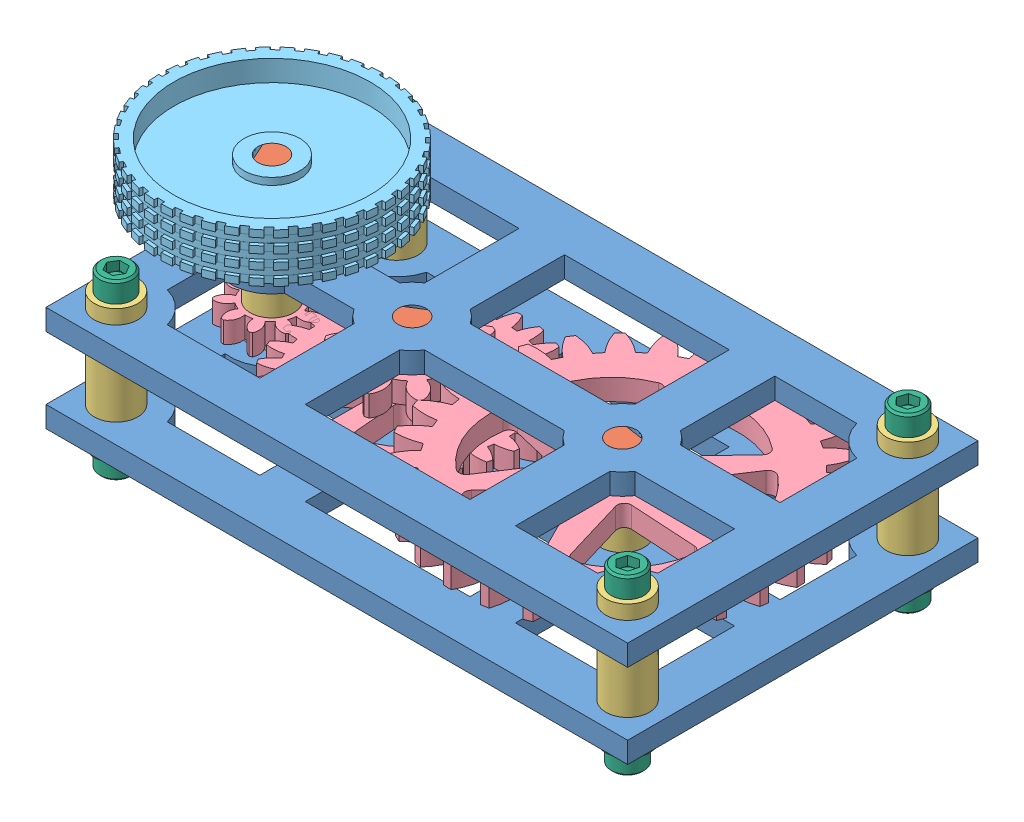
SolidWorks assembly gearbox, configuration Default. Lengths in mm.
Overall size (99.85 37 54.33).
40 component instances, 6 part files, 46 mates.
Components (placement in the parent):
- plate-1: plate [Default] at (38.6183 41.2448 69.3002) size (83 3 50)
- subassem1-1: subassem1 [Default] at (-22.9278 69.7398 72.0487) x (0.409476 0 0.912321) z (0.912321 0 -0.409476) size (12 25 11.53)
  - axel-1: axel [25 tall] at (8.6695 3.495 26.0282) size (4 25 3.5)
  - spacer-1: spacer [1 mm tall] at (8.6695 24.495 26.0282) x (0.916375 0 -0.400322) z (0.400322 0 0.916375) size (6.2 1 6.2)
  - spacer-2: spacer [5mm tall] at (8.6695 16.495 26.0282) x (-0.921754 0 0.387775) z (-0.387775 0 -0.921754) size (6.2 5 6.2)
  - root_gear-1: root_gear [10T 1.0Mod] at (8.6695 21.495 26.0282) size (12 3 11.53)
- subassem2-1: subassem2 [Default] at (24.0007 53.9541 53.6802) x (-0.845445 0 0.534063) z (0.534063 0 0.845445) size (32 15 31.89)
  - root_gear-3: root_gear [30T 1.0Mod] at (8.0314 5.7093 13.4022) size (32 3 31.89)
  - root_gear-4: root_gear [10T 1.5Mod] at (8.0314 1.7093 13.4022) size (18 3 17.3)
  - axel-1: axel [15 tall] at (8.0314 -2.2907 13.4022) size (4 15 3.5)
  - spacer-1: spacer [1 mm tall] at (8.0314 0.7093 13.4022) x (-0.679343 0 -0.733821) z (0.733821 0 -0.679343) size (6.2 1 6.2)
  - spacer-2: spacer [1 mm tall] at (8.0314 4.7093 13.4022) x (0.793961 0 -0.607968) z (0.607968 0 0.793961) size (6.2 1 6.2)
  - spacer-3: spacer [1 mm tall] at (8.0314 8.7093 13.4022) x (0.998465 0 -0.055384) z (0.055384 0 0.998465) size (6.2 1 6.2)
- subassem3-1: subassem3 [Default] at (45.6057 27.3395 43.9522) x (0.989309 0 0.145833) z (-0.145833 0 0.989309) size (48 25 47.84)
  - axel-1: axel [25 tall] at (12.3654 3.9053 23.7992) size (4 25 3.5)
  - root_gear-1: root_gear [30T 1.5Mod] at (12.3654 21.9053 23.7992) size (48 3 47.84)
  - spacer-1: spacer [1 mm tall] at (12.3654 24.9053 23.7992) x (0.97373 0 -0.227706) z (0.227706 0 0.97373) size (6.2 1 6.2)
  - spacer-2: spacer [5mm tall] at (12.3654 16.9053 23.7992) size (6.2 5 6.2)
- knob-1: knob [Default] at (4.3683 61.2448 69.3002) x (0 1 0) z (0.692524 0 0.721395) size (7 31.99 31.98)
- plate-2: plate [Default] at (38.6183 53.2448 69.3002) size (83 3 50)
- spacer-1: spacer [2.85 mm ID] at (2.1183 44.2448 89.3002) x (0.5813 0 0.813689) z (-0.813689 0 0.5813) size (6.2 9 6.2)
- spacer-2: spacer [2.85 mm ID] at (75.1183 44.2448 49.3002) x (0.5813 0 0.813689) z (-0.813689 0 0.5813) size (6.2 9 6.2)
- spacer-3: spacer [2.85 mm ID] at (2.1183 44.2448 49.3002) x (0.408871 0 0.912592) z (-0.912592 0 0.408871) size (6.2 9 6.2)
- spacer-4: spacer [2.85 mm ID] at (75.1183 44.2448 89.3002) x (0.525156 0 0.851006) z (-0.851006 0 0.525156) size (6.2 9 6.2)
- spacer-5: spacer [smaller 2.85 mm ID] at (2.1183 56.2448 89.3002) x (0.059353 0 0.998237) z (-0.998237 0 0.059353) size (6.2 2.02 6.2)
- spacer-6: spacer [smaller 2.85 mm ID] at (2.1183 56.2448 49.3002) x (-0.028098 0 0.999605) z (-0.999605 0 -0.028098) size (6.2 2.02 6.2)
- spacer-7: spacer [smaller 2.85 mm ID] at (75.1183 39.2198 49.3002) x (0.564051 0 0.82574) z (-0.82574 0 0.564051) size (6.2 2.02 6.2)
- spacer-8: spacer [smaller 2.85 mm ID] at (75.1183 41.2448 89.3002) x (-0.292272 0 0.956335) z (0.956335 0 0.292272) size (6.2 2.02 6.2)
- spacer-9: spacer [smaller 2.85 mm ID] at (2.1183 41.2448 89.3002) x (-0.425806 0 0.904815) z (0.904815 0 0.425806) size (6.2 2.02 6.2)
- spacer-10: spacer [smaller 2.85 mm ID] at (2.1183 41.2448 49.3002) x (-0.591521 0 0.806289) z (0.806289 0 0.591521) size (6.2 2.02 6.2)
- spacer-11: spacer [smaller 2.85 mm ID] at (75.1183 56.2448 89.3002) x (-0.618307 0 0.785937) z (-0.785937 0 -0.618307) size (6.2 2.02 6.2)
- spacer-12: spacer [smaller 2.85 mm ID] at (75.1183 56.2448 49.3002) x (0.472536 0 0.881311) z (-0.881311 0 0.472536) size (6.2 2.02 6.2)
- socket head cap screw_ai-1: socket head cap screw_ai [HX-SHCS 0.112-40x0.375x0.375-N] at (75.1183 36.375 89.3002) x (0 1 0) z (-0.37265 0 0.927972) size (12.37 4.65 4.65)
- socket head cap screw_ai-2: socket head cap screw_ai [HX-SHCS 0.112-40x0.375x0.375-N] at (75.1183 61.1146 89.3002) x (0 -1 0) z (0.2511 0 0.967961) size (12.37 4.65 4.65)
- socket head cap screw_ai-3: socket head cap screw_ai [HX-SHCS 0.112-40x0.375x0.375-N] at (2.1183 36.375 89.3002) x (0 1 0) z (-0.769807 0 -0.638277) size (12.37 4.65 4.65)
- socket head cap screw_ai-4: socket head cap screw_ai [HX-SHCS 0.112-40x0.375x0.375-N] at (2.1183 61.1146 49.3002) x (0 -1 0) z (0.951892 0 -0.306432) size (12.37 4.65 4.65)
- socket head cap screw_ai-5: socket head cap screw_ai [HX-SHCS 0.112-40x0.375x0.375-N] at (75.1183 61.1146 49.3002) x (0 -1 0) z (0.214562 0 0.97671) size (12.37 4.65 4.65)
- socket head cap screw_ai-6: socket head cap screw_ai [HX-SHCS 0.112-40x0.375x0.375-N] at (75.1183 36.375 49.3002) x (0 1 0) z (0.568945 0 -0.822375) size (12.37 4.65 4.65)
- socket head cap screw_ai-7: socket head cap screw_ai [HX-SHCS 0.112-40x0.375x0.375-N] at (2.1183 36.375 49.3002) x (0 1 0) z (-0.639188 0 0.769051) size (12.37 4.65 4.65)
- socket head cap screw_ai-8: socket head cap screw_ai [HX-SHCS 0.112-40x0.375x0.375-N] at (2.1183 61.1146 89.3002) x (0 -1 0) z (0.869562 0 -0.493824) size (12.37 4.65 4.65)
Mates (geometry in assembly coordinates):
- Coincident2: coincident: plane of plate-1 through (38.6183 44.2448 69.3002) normal (0 1 0); plane of subassem2-1/spacer-3 through (24.3683 44.2448 69.3002) normal (0 -1 0)
- Concentric2: concentric: cylinder of plate-1 through (24.3683 44.2448 69.3002) axis (0 -1 0) radius 2; cylinder of subassem2-1/axel-1 through (24.3683 41.2448 69.3002) axis (0 1 0) radius 2
- Concentric3: concentric: cylinder of plate-1 through (4.3683 44.2448 69.3002) axis (0 -1 0) radius 2; cylinder of subassem1-1/axel-1 through (4.3683 41.2448 69.3002) axis (0 1 0) radius 2
- Coincident3: coincident: plane of plate-1 through (38.6183 44.2448 69.3002) normal (0 1 0); plane of subassem1-1/spacer-1 through (4.3683 44.2448 69.3002) normal (0 -1 0)
- Concentric4: concentric: cylinder of plate-1 through (54.3683 44.2448 69.3002) axis (0 -1 0) radius 2; cylinder of subassem3-1/axel-1 through (54.3683 56.2448 69.3002) axis (0 -1 0) radius 2
- Coincident5: coincident: plane of subassem2-1/root_gear-4 through (24.3683 52.2448 69.3002) normal (0 1 0); plane of subassem3-1/root_gear-1 through (54.3683 52.2448 69.3002) normal (0 1 0)
- GearMate1: gear = 11.25 : 48 mm: cylinder of subassem3-1/root_gear-1 through (54.3683 52.2448 69.3002) axis (0 -1 0) radius 24; cylinder of subassem2-1/root_gear-4 through (24.3683 52.2448 69.3002) axis (0 -1 0) radius 5.625
- GearMate2: gear = 27.5 : 12 mm: cylinder of subassem1-1/root_gear-1 through (4.3683 45.2448 69.3002) axis (0 1 0) radius 6; cylinder of subassem2-1/root_gear-3 through (24.3683 48.2448 69.3002) axis (0 -1 0) radius 13.75
- Concentric6: concentric: circle of plate-1; circle of plate-2
- Concentric7: concentric: circle of plate-1; circle of plate-2
- Coincident8: coincident: plane of subassem1-1/spacer-2 through (4.3683 53.2448 69.3002) normal (0 1 0); plane of plate-2 through (38.6183 53.2448 69.3002) normal (0 -1 0)
- Coincident9: coincident: plane of subassem1-1/axel-1 through (4.3683 66.2448 69.3002) normal (0 1 0); plane of knob-1 through (1.4827 66.2448 72.0703) normal (0 1 0)
- Concentric8: concentric: cylinder of subassem1-1/axel-1 through (4.3683 41.2448 69.3002) axis (0 1 0) radius 2; cylinder of knob-1 through (4.3683 61.2448 69.3002) axis (0 -1 0) radius 2
- Coincident10: coincident: plane of plate-2 through (38.6183 56.2448 69.3002) normal (0 1 0); plane of spacer-12 through (75.1183 56.2448 49.3002) normal (0 -1 0)
- Concentric9: concentric: cylinder of plate-2 through (75.1183 56.2448 49.3002) axis (0 -1 0) radius 1.425; circle of spacer-12
- Coincident13: coincident: circle of plate-2; circle of spacer-11
- Coincident14: coincident: circle of plate-2; circle of spacer-5
- Coincident15: coincident: circle of plate-2; circle of spacer-6
- Coincident16: coincident: circle of plate-1; circle of spacer-7
- Coincident17: coincident: circle of plate-1; circle of spacer-8
- Coincident18: coincident: circle of plate-1; circle of spacer-9
- Coincident19: coincident: circle of plate-1; circle of spacer-10
- Coincident20: coincident: plane of spacer-11 through (75.1183 58.2698 89.3002) normal (0 1 0); plane of socket head cap screw_ai-2 through (77.3679 58.2698 88.7166) normal (0 -1 0)
- Concentric11: concentric: cylinder of spacer-11 through (75.1183 56.2448 89.3002) axis (0 1 0) radius 1.425; cylinder of socket head cap screw_ai-2 through (75.1183 92.8646 89.3002) axis (0 1 0) radius 1.4224
- Coincident21: coincident: plane of spacer-8 through (75.1183 39.2198 89.3002) normal (0 -1 0); plane of socket head cap screw_ai-1 through (72.9616 39.2198 88.4341) normal (0 1 0)
- Concentric12: concentric: cylinder of spacer-8 through (75.1183 41.2448 89.3002) axis (0 -1 0) radius 1.425; cylinder of socket head cap screw_ai-1 through (75.1183 4.625 89.3002) axis (0 -1 0) radius 1.4224
- Concentric13: concentric: cylinder of spacer-4 through (75.1183 44.2448 89.3002) axis (0 1 0) radius 1.425; cylinder of socket head cap screw_ai-1 through (75.1183 4.625 89.3002) axis (0 -1 0) radius 1.4224
- Coincident23: coincident: plane of plate-2 through (38.6183 53.2448 69.3002) normal (0 -1 0); plane of spacer-4 through (75.1183 53.2448 89.3002) normal (0 1 0)
- Coincident24: coincident: plane of spacer-9 through (2.1183 39.2198 89.3002) normal (0 -1 0); plane of socket head cap screw_ai-3 through (3.6017 39.2198 87.5111) normal (0 1 0)
- Concentric14: concentric: cylinder of spacer-9 through (2.1183 41.2448 89.3002) axis (0 -1 0) radius 1.425; cylinder of socket head cap screw_ai-3 through (2.1183 4.625 89.3002) axis (0 -1 0) radius 1.4224
- Coincident26: coincident: plane of spacer-5 through (2.1183 58.2698 89.3002) normal (0 1 0); plane of socket head cap screw_ai-8 through (0.9706 58.2698 87.2793) normal (0 -1 0)
- Concentric15: concentric: cylinder of spacer-5 through (2.1183 56.2448 89.3002) axis (0 1 0) radius 1.425; cylinder of socket head cap screw_ai-8 through (2.1183 92.8646 89.3002) axis (0 1 0) radius 1.4224
- Concentric16: concentric: cylinder of spacer-1 through (2.1183 44.2448 89.3002) axis (0 1 0) radius 1.425; cylinder of socket head cap screw_ai-8 through (2.1183 92.8646 89.3002) axis (0 1 0) radius 1.4224
- Coincident27: coincident: plane of plate-1 through (38.6183 44.2448 69.3002) normal (0 1 0); plane of spacer-1 through (2.1183 44.2448 89.3002) normal (0 -1 0)
- Coincident28: coincident: plane of spacer-12 through (75.1183 58.2698 49.3002) normal (0 1 0); plane of socket head cap screw_ai-5 through (77.3882 58.2698 48.8015) normal (0 -1 0)
- Concentric17: concentric: cylinder of spacer-12 through (75.1183 56.2448 49.3002) axis (0 1 0) radius 1.425; cylinder of socket head cap screw_ai-5 through (75.1183 92.8646 49.3002) axis (0 1 0) radius 1.4224
- Coincident29: coincident: plane of spacer-7 through (75.1183 39.2198 49.3002) normal (0 -1 0); plane of socket head cap screw_ai-6 through (77.0295 39.2198 50.6225) normal (0 1 0)
- Concentric18: concentric: cylinder of spacer-7 through (75.1183 39.2198 49.3002) axis (0 1 0) radius 1.425; cylinder of socket head cap screw_ai-6 through (75.1183 4.625 49.3002) axis (0 -1 0) radius 1.4224
- Concentric19: concentric: cylinder of spacer-2 through (75.1183 44.2448 49.3002) axis (0 1 0) radius 1.425; cylinder of socket head cap screw_ai-5 through (75.1183 92.8646 49.3002) axis (0 1 0) radius 1.4224
- Coincident30: coincident: plane of plate-1 through (38.6183 44.2448 69.3002) normal (0 1 0); plane of spacer-2 through (75.1183 44.2448 49.3002) normal (0 -1 0)
- Coincident31: coincident: plane of spacer-10 through (2.1183 39.2198 49.3002) normal (0 -1 0); plane of socket head cap screw_ai-7 through (0.3309 39.2198 47.8147) normal (0 1 0)
- Concentric20: concentric: cylinder of spacer-10 through (2.1183 41.2448 49.3002) axis (0 -1 0) radius 1.425; cylinder of socket head cap screw_ai-7 through (2.1183 4.625 49.3002) axis (0 -1 0) radius 1.4224
- Coincident32: coincident: plane of spacer-6 through (2.1183 58.2698 49.3002) normal (0 1 0); plane of socket head cap screw_ai-4 through (1.4061 58.2698 47.0879) normal (0 -1 0)
- Concentric21: concentric: cylinder of spacer-6 through (2.1183 56.2448 49.3002) axis (0 1 0) radius 1.425; cylinder of socket head cap screw_ai-4 through (2.1183 92.8646 49.3002) axis (0 1 0) radius 1.4224
- Concentric22: concentric: cylinder of spacer-3 through (2.1183 44.2448 49.3002) axis (0 1 0) radius 1.425; cylinder of socket head cap screw_ai-7 through (2.1183 4.625 49.3002) axis (0 -1 0) radius 1.4224
- Coincident33: coincident: plane of plate-2 through (38.6183 53.2448 69.3002) normal (0 -1 0); plane of spacer-3 through (2.1183 53.2448 49.3002) normal (0 1 0)
